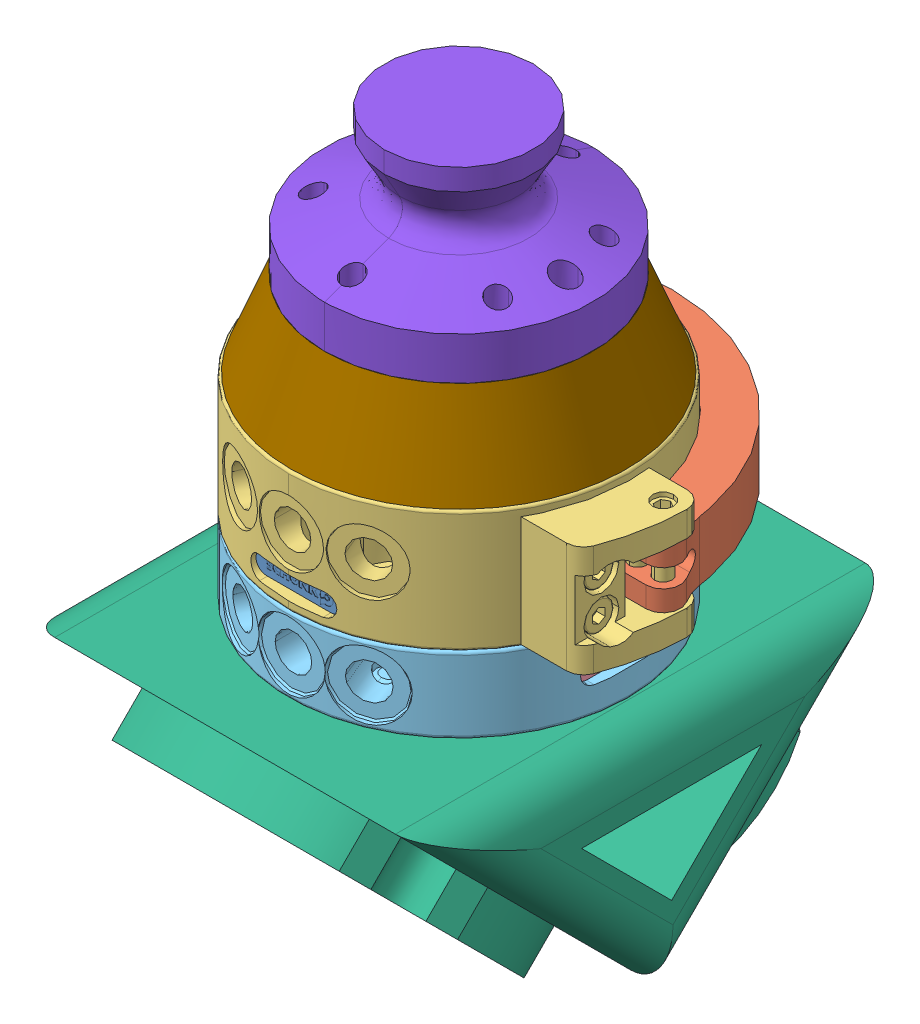
SolidWorks assembly interfaccia_nostrana_con_interfaccia_schunk, configuration Default. Lengths in mm.
Overall size (102.61 169.8 124.45).
18 component instances, 9 part files, 28 mates.
Components (placement in the parent):
- SCHUNK_0310420_SHK_063_000_000_0000ohne-1: SCHUNK_0310420_SHK_063_000_000_0000ohne [Default] at (49.5147 44.4186 59.3936) size (92.63 36.89 94.12)
  - SCHUNK_0310420_SHK_063_000_000_0000ohne_3-1: SCHUNK_0310420_SHK_063_000_000_0000ohne_3 [Default] at (0 4.7 37.3) size (20 5 0.3)
  - SCHUNK_0310420_SHK_063_000_000_0000ohne_5-1: SCHUNK_0310420_SHK_063_000_000_0000ohne_5 [Default] at (0 13.4 0) x (0 0 1) z (-1 0 0) size (58.11 14 86.81)
  - SCHUNK_0310420_SHK_063_000_000_0000ohne_7-1: SCHUNK_0310420_SHK_063_000_000_0000ohne_7 [Default] x (-1 0 0) z (0 0 -1) size (92.63 36.89 80.01)
- SCHUNK_0310421_SHA_063_000_000_0000ohne-1: SCHUNK_0310421_SHA_063_000_000_0000ohne [Default] at (49.5147 44.4186 59.3936) size (80 40.89 80.02)
  - SCHUNK_0310421_SHA_063_000_000_0000ohne_3-1: SCHUNK_0310421_SHA_063_000_000_0000ohne_3 [Default] at (37.3 -9 0) x (0 0 -1) z (1 0 0) size (20 5 0.3)
  - SCHUNK_0310421_SHA_063_000_000_0000ohne_5-1: SCHUNK_0310421_SHA_063_000_000_0000ohne_5 [Default] at origin size (80 40.89 80.02)
- interfaccia_doppio_gripper-1: interfaccia_doppio_gripper [Default] at (109.0517 32.3987 -24.8257) x (-1 0 0) z (0 0.707107 0.707107) size (100 88 88)
- socket head cap screw_iso-2: socket head cap screw_iso [ISO 4762 M6 x 20 - 20N] at (27.2408 43.6186 37.1197) x (0 -1 0) z (0 0 1) size (26 10 10)
- socket head cap screw_iso-3: socket head cap screw_iso [ISO 4762 M6 x 20 - 20N] at (71.7885 43.6186 37.1197) x (0 -1 0) z (0 0 1) size (26 10 10)
- socket head cap screw_iso-4: socket head cap screw_iso [ISO 4762 M6 x 20 - 20N] at (71.7885 43.6186 81.6675) x (0 -1 0) z (0 0 1) size (26 10 10)
- socket head cap screw_iso-5: socket head cap screw_iso [ISO 4762 M6 x 20 - 20N] at (27.2408 43.6186 81.6675) x (0 -1 0) z (0 0 1) size (26 10 10)
- IRB4600_20kg-250_LINK6_CAD_rev04-1: IRB4600_20kg-250_LINK6_CAD_rev04 [Default] at (-1715.4853 1583.4186 59.3936) x (0 -1 0) z (1 0 0) size (34 63 63)
- Parte4^interfaccia_nostrana_con_interfaccia_schunk-1: Parte4^interfaccia_nostrana_con_interfaccia_schunk [Default] at (49.5147 72.9186 59.3936) x (-1 0 0) z (0 1 0) size (78.8 78.8 20) (virtual)
- socket head cap screw_iso-6: socket head cap screw_iso [ISO 4762 M6 x 45 - 24N] at (71.7885 45.2186 37.1197) x (0 1 0) z (0 0 1) size (26 10 10)
- socket head cap screw_iso-7: socket head cap screw_iso [ISO 4762 M6 x 20 - 20N] at (71.7885 45.2186 81.6675) x (0 1 0) z (0 0 1) size (26 10 10)
- socket head cap screw_iso-8: socket head cap screw_iso [ISO 4762 M6 x 45 - 24N] at (27.2408 45.2186 37.1197) x (0 1 0) z (0 0 1) size (26 10 10)
- socket head cap screw_iso-9: socket head cap screw_iso [ISO 4762 M6 x 45 - 24N] at (27.2408 45.2186 81.6675) x (0 1 0) z (0 0 1) size (26 10 10)
Mates (geometry in assembly coordinates):
- Coincidente1: coincident anti-aligned: plane of SCHUNK_0310421_SHA_063_000_000_0000ohne-1/SCHUNK_0310421_SHA_063_000_000_0000ohne_5-1 through (70.3247 26.4186 59.3936) normal (0 -1 0); plane of interfaccia_doppio_gripper-1 through (99.5147 26.4186 114.2402) normal (0 1 0)
- Coincidente2: coincident aligned: plane of SCHUNK_0310421_SHA_063_000_000_0000ohne-1/SCHUNK_0310421_SHA_063_000_000_0000ohne_5-1 through (49.5147 44.4186 59.3936) normal (1 0 0); plane of interfaccia_doppio_gripper-1 through (49.5147 32.3987 -24.8257) normal (1 0 0)
- Coincidente3: coincident: plane of SCHUNK_0310421_SHA_063_000_000_0000ohne-1 through (49.5147 44.4186 59.3936) normal (0 0 1); line of interfaccia_doppio_gripper-1 through (-0.4853 -9.4696 59.3936) axis (1 0 0)
- Concentrico3: concentric anti-aligned: cylinder of SCHUNK_0310421_SHA_063_000_000_0000ohne-1/SCHUNK_0310421_SHA_063_000_000_0000ohne_5-1 through (27.2408 26.4186 37.1197) axis (0 -1 0) radius 3.3235; cylinder of socket head cap screw_iso-2 through (27.2408 75.3686 37.1197) axis (0 1 0) radius 5
- Coincidente7: coincident anti-aligned: plane of SCHUNK_0310421_SHA_063_000_000_0000ohne-1/SCHUNK_0310421_SHA_063_000_000_0000ohne_5-1 through (31.1299 37.6186 33.2307) normal (0 1 0); plane of socket head cap screw_iso-2 through (32.2408 37.6186 37.1197) normal (0 -1 0)
- Concentrico4: concentric anti-aligned: cylinder of SCHUNK_0310421_SHA_063_000_000_0000ohne-1/SCHUNK_0310421_SHA_063_000_000_0000ohne_5-1 through (71.7885 26.4186 37.1197) axis (0 -1 0) radius 3.3235; cylinder of socket head cap screw_iso-3 through (71.7885 75.3686 37.1197) axis (0 1 0) radius 5
- Coincidente8: coincident anti-aligned: plane of SCHUNK_0310421_SHA_063_000_000_0000ohne-1/SCHUNK_0310421_SHA_063_000_000_0000ohne_5-1 through (75.6776 37.6186 33.2307) normal (0 1 0); plane of socket head cap screw_iso-3 through (76.7885 37.6186 37.1197) normal (0 -1 0)
- Concentrico5: concentric anti-aligned: cylinder of SCHUNK_0310421_SHA_063_000_000_0000ohne-1/SCHUNK_0310421_SHA_063_000_000_0000ohne_5-1 through (71.7885 26.4186 81.6675) axis (0 -1 0) radius 5.5; cylinder of socket head cap screw_iso-4 through (71.7885 75.3686 81.6675) axis (0 1 0) radius 5
- Coincidente9: coincident anti-aligned: plane of SCHUNK_0310421_SHA_063_000_000_0000ohne-1/SCHUNK_0310421_SHA_063_000_000_0000ohne_5-1 through (75.6776 37.6186 77.7784) normal (0 1 0); plane of socket head cap screw_iso-4 through (76.7885 37.6186 81.6675) normal (0 -1 0)
- Concentrico6: concentric anti-aligned: cylinder of SCHUNK_0310421_SHA_063_000_000_0000ohne-1/SCHUNK_0310421_SHA_063_000_000_0000ohne_5-1 through (27.2408 26.4186 81.6675) axis (0 -1 0) radius 3.3235; cylinder of socket head cap screw_iso-5 through (27.2408 75.3686 81.6675) axis (0 1 0) radius 5
- Coincidente10: coincident anti-aligned: plane of SCHUNK_0310421_SHA_063_000_000_0000ohne-1/SCHUNK_0310421_SHA_063_000_000_0000ohne_5-1 through (31.1299 37.6186 77.7784) normal (0 1 0); plane of socket head cap screw_iso-5 through (32.2408 37.6186 81.6675) normal (0 -1 0)
- Concentrico9: concentric aligned: cylinder of SCHUNK_0310420_SHK_063_000_000_0000ohne-1/SCHUNK_0310420_SHK_063_000_000_0000ohne_7-1 through (49.5147 72.9186 59.3936) axis (0 -1 0) radius 40; cylinder of IRB4600_20kg-250_LINK6_CAD_rev04-1 through (49.5147 92.9186 59.3936) axis (0 -1 0) radius 31.5
- Distanza1: distance = 20 mm anti-aligned: plane of SCHUNK_0310420_SHK_063_000_000_0000ohne-1/SCHUNK_0310420_SHK_063_000_000_0000ohne_7-1 through (49.5147 72.9186 59.3936) normal (0 1 0); plane of IRB4600_20kg-250_LINK6_CAD_rev04-1 through (49.5147 92.9186 43.6436) normal (0 -1 0)
- Concentrico10: concentric aligned: cylinder of SCHUNK_0310420_SHK_063_000_000_0000ohne-1/SCHUNK_0310420_SHK_063_000_000_0000ohne_7-1 through (49.5147 72.9186 59.3936) axis (0 -1 0) radius 20.01; cylinder of IRB4600_20kg-250_LINK6_CAD_rev04-1 through (49.5147 92.9186 59.3936) axis (0 -1 0) radius 17.5
- SulPosto2: in place: plane of SCHUNK_0310420_SHK_063_000_000_0000ohne-1/SCHUNK_0310420_SHK_063_000_000_0000ohne_7-1 through (49.5147 72.9186 59.3936) normal (0 1 0); plane of ? through (0 72.9186 0) normal (0 1 0); moOrthogonalPlaneRef_w of SCHUNK_0310420_SHK_063_000_000_0000ohne-1/SCHUNK_0310420_SHK_063_000_000_0000ohne_7-1 through (49.5147 72.9186 59.3936) normal (0 1 0); plane of ? through (0 72.9186 0) normal (0 0 -1); plane of SCHUNK_0310420_SHK_063_000_000_0000ohne-1/SCHUNK_0310420_SHK_063_000_000_0000ohne_7-1 through (49.5147 72.9186 59.3936) normal (0 1 0); plane of ? through (0 72.9186 0) normal (1 0 0); plane of SCHUNK_0310420_SHK_063_000_000_0000ohne-1/SCHUNK_0310420_SHK_063_000_000_0000ohne_7-1 through (49.5147 72.9186 59.3936) normal (0 1 0); unknown of Parte4^interfaccia_nostrana_con_interfaccia_schunk-1
- Coincidente21: coincident aligned: plane of SCHUNK_0310420_SHK_063_000_000_0000ohne-1/SCHUNK_0310420_SHK_063_000_000_0000ohne_7-1; plane of Parte4^interfaccia_nostrana_con_interfaccia_schunk-1
- Coincidente22: coincident aligned: moOrthogonalPlaneRef_w of SCHUNK_0310420_SHK_063_000_000_0000ohne-1/SCHUNK_0310420_SHK_063_000_000_0000ohne_7-1 through (49.5147 72.9186 59.3936) normal (0 0 1); plane of Parte4^interfaccia_nostrana_con_interfaccia_schunk-1 through (49.5147 72.9186 59.3936) normal (0 0 1)
- Coincidente23: coincident anti-aligned: moOrthogonalPlaneRef_w of SCHUNK_0310420_SHK_063_000_000_0000ohne-1/SCHUNK_0310420_SHK_063_000_000_0000ohne_7-1 through (49.5147 72.9186 59.3936) normal (1 0 0); plane of Parte4^interfaccia_nostrana_con_interfaccia_schunk-1 through (49.5147 72.9186 59.3936) normal (-1 0 0)
- Concentrico12: concentric aligned: cylinder of SCHUNK_0310420_SHK_063_000_000_0000ohne-1/SCHUNK_0310420_SHK_063_000_000_0000ohne_7-1 through (71.7885 44.4186 37.1197) axis (0 -1 0) radius 5.5; cylinder of socket head cap screw_iso-6 through (71.7885 13.4686 37.1197) axis (0 -1 0) radius 5
- Coincidente24: coincident anti-aligned: plane of SCHUNK_0310420_SHK_063_000_000_0000ohne-1/SCHUNK_0310420_SHK_063_000_000_0000ohne_7-1 through (68.9601 51.2186 34.2913) normal (0 -1 0); plane of socket head cap screw_iso-6 through (66.7885 51.2186 37.1197) normal (0 1 0)
- Concentrico13: concentric anti-aligned: cone of SCHUNK_0310420_SHK_063_000_000_0000ohne-1/SCHUNK_0310420_SHK_063_000_000_0000ohne_7-1 through (71.7885 51.8951 81.6675) axis (0 1 0); cylinder of socket head cap screw_iso-7 through (71.7885 13.4686 81.6675) axis (0 -1 0) radius 5
- Coincidente25: coincident anti-aligned: plane of SCHUNK_0310420_SHK_063_000_000_0000ohne-1/SCHUNK_0310420_SHK_063_000_000_0000ohne_7-1 through (68.9601 51.2186 78.839) normal (0 -1 0); plane of socket head cap screw_iso-7 through (66.7885 51.2186 81.6675) normal (0 1 0)
- Concentrico14: concentric aligned: cylinder of SCHUNK_0310420_SHK_063_000_000_0000ohne-1/SCHUNK_0310420_SHK_063_000_000_0000ohne_7-1 through (27.2408 44.4186 37.1197) axis (0 -1 0) radius 5.5; cylinder of socket head cap screw_iso-8 through (27.2408 13.4686 37.1197) axis (0 -1 0) radius 5
- Coincidente26: coincident anti-aligned: plane of SCHUNK_0310420_SHK_063_000_000_0000ohne-1/SCHUNK_0310420_SHK_063_000_000_0000ohne_7-1 through (24.4124 51.2186 34.2913) normal (0 -1 0); plane of socket head cap screw_iso-8 through (22.2408 51.2186 37.1197) normal (0 1 0)
- Concentrico15: concentric aligned: cylinder of SCHUNK_0310420_SHK_063_000_000_0000ohne-1/SCHUNK_0310420_SHK_063_000_000_0000ohne_7-1 through (27.2408 44.4186 81.6675) axis (0 -1 0) radius 5.5; cylinder of socket head cap screw_iso-9 through (27.2408 13.4686 81.6675) axis (0 -1 0) radius 5
- Coincidente27: coincident anti-aligned: plane of SCHUNK_0310420_SHK_063_000_000_0000ohne-1/SCHUNK_0310420_SHK_063_000_000_0000ohne_7-1 through (24.4124 51.2186 78.839) normal (0 -1 0); plane of socket head cap screw_iso-9 through (22.2408 51.2186 81.6675) normal (0 1 0)
- Concentrico16: concentric aligned: cylinder of SCHUNK_0310420_SHK_063_000_000_0000ohne-1/SCHUNK_0310420_SHK_063_000_000_0000ohne_7-1 through (12.6147 57.9186 59.3936) axis (-1 0 0) radius 8.005; cylinder of SCHUNK_0310421_SHA_063_000_000_0000ohne-1/SCHUNK_0310421_SHA_063_000_000_0000ohne_5-1 through (89.5147 57.9186 59.3936) axis (-1 0 0) radius 7.98
- Concentrico17: concentric aligned: cylinder of SCHUNK_0310420_SHK_063_000_000_0000ohne-1/SCHUNK_0310420_SHK_063_000_000_0000ohne_7-1 through (49.5147 72.9186 59.3936) axis (0 -1 0) radius 20.01; cylinder of SCHUNK_0310421_SHA_063_000_000_0000ohne-1/SCHUNK_0310421_SHA_063_000_000_0000ohne_5-1 through (49.5147 26.4186 59.3936) axis (0 -1 0) radius 19.99
